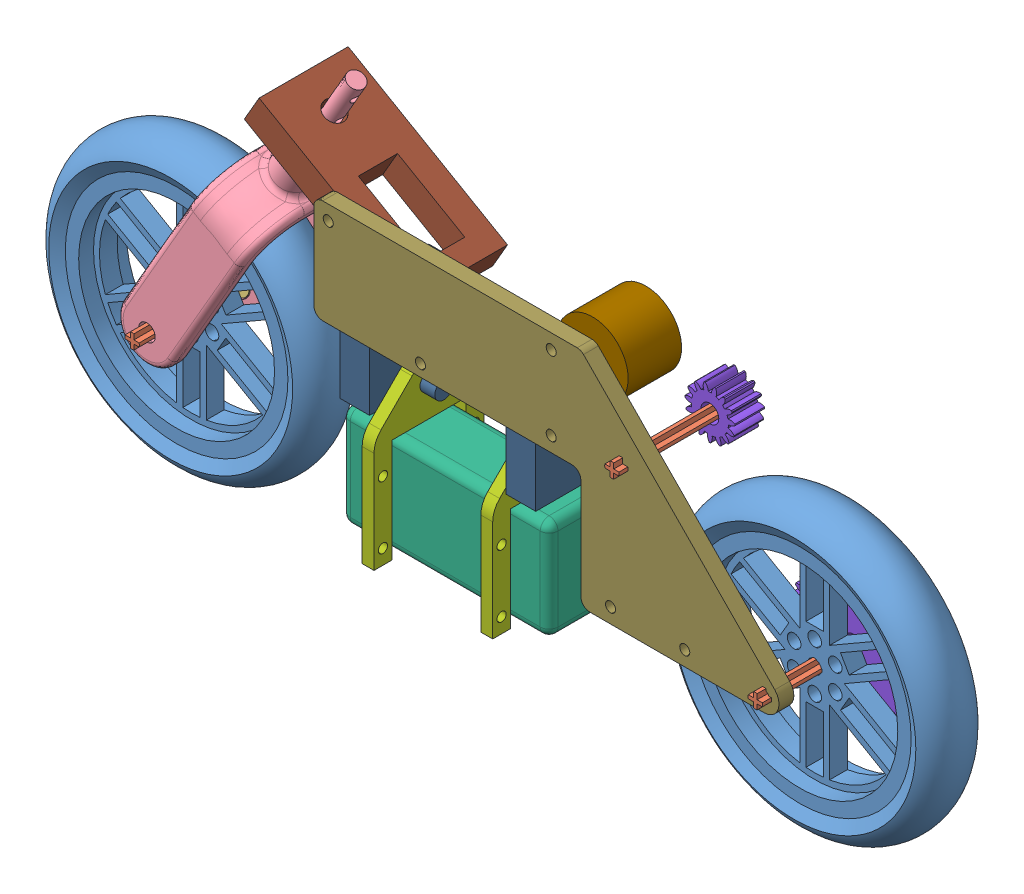
SolidWorks assembly assembly_v3.1, configuration 默认. Lengths in mm.
Overall size (305 143.43 89.5).
19 component instances, 12 part files, 41 mates.
Components (placement in the parent):
- tire_v2.0-1: tire_v2.0 [默认] at (-32.3319 -6.7834 95) size (95 95 20)
- axle_v1.0-1: axle_v1.0 [默认] at (-32.3319 -6.7834 95) x (0 0 -1) z (1 0 0) size (46 4.9 4.9)
- bearing_MR95ZZ-1: bearing_MR95ZZ [默认] at (-32.3319 -6.7834 110) x (0 0 -1) z (1 0 0) size (3 9 9)
- bearing_MR95ZZ-2: bearing_MR95ZZ [默认] at (-32.3319 -6.7834 83) x (0 0 -1) z (1 0 0) size (3 9 9)
- front_fork_v2.2-1: front_fork_v2.2 [默认] at (-2.3319 45.1782 95) x (0 0 -1) z (0.866025 -0.5 0) size (36 115 20)
- bearing_686ZZ-1: bearing_686ZZ [默认] at (7.8681 62.8451 95) x (0.5 0.866025 0) z (0 0 1) size (5 13 13)
- battery_v2.0-1: battery_v2.0 [默认] at (60.682 -20 95) x (-1 0 0) z (0 0 1) size (70 34 21)
- tire_v2.0-2: tire_v2.0 [默认] at (177.6681 -6.7834 95) size (95 95 20)
- battery_holder-1: battery_holder [默认] at (40.682 -37.5 95) x (0 0 -1) z (1 0 0) size (37 52.69 4)
- battery_holder-2: battery_holder [默认] at (80.682 -37.5 95) x (0 0 -1) z (1 0 0) size (37 52.69 4)
- spur gear_gb-2: spur gear_gb [GB - Spur gear 1M 40T 20PA 10FW ---S40A75H50L6.0N] at (177.6681 -6.7834 85) x (0 0 -1) z (1 0 0) size (10 41.91 41.91)
- spur gear_gb-4: spur gear_gb [GB - Spur gear 1M 15T 20PA 10FW ---S15A75H50L6.0N] at (129.3618 36.3945 85) x (0 0 -1) z (1 0 0) size (10 16.86 16.95)
- axle_v1.0-2: axle_v1.0 [默认] at (177.6681 -6.7834 95) x (0 0 -1) z (1 0 0) size (46 4.9 4.9)
- axle_v1.0-3: axle_v1.0 [默认] at (129.3618 36.3945 95) x (0 0 -1) z (1 0 0) size (46 4.9 4.9)
- motor_v1.0-1: motor_v1.0 [默认] at (107.8169 50.8219 85) x (0 0 1) z (-1 0 0) size (26 24 24)
- battery_frame_v1.0-1: battery_frame_v1.0 [默认] at (34.682 18.5 80) x (0 0 1) z (-1 0 0) size (30 30 20)
- battery_frame_v1.0-2: battery_frame_v1.0 [默认] at (90.682 18.5 110) x (0 0 -1) z (1 0 0) size (30 30 20)
- fork_frame_v1.0-1: fork_frame_v1.0 [默认] at (10.3681 67.1752 95) x (0 0 1) z (-0.866025 0.5 0) size (30 10 62)
- side_plate_v1.0-1: side_plate_v1.0 [默认] at (115.8979 -11.7834 110) x (0 0 1) z (-1 0 0) size (86.5 90.86 175.34)
Mates (geometry in assembly coordinates):
- 重合1: coincident anti-aligned: plane of tire_v2.0-1 through (-32.3319 -6.7834 95) normal (0 0 1); plane of axle_v1.0-1 through (-32.3319 -6.7834 95) normal (0 0 -1)
- 同心1: concentric anti-aligned: circle of tire_v2.0-1; circle of axle_v1.0-1
- 同心2: concentric anti-aligned: circle of bearing_MR95ZZ-1; circle of tire_v2.0-1
- 同心3: concentric anti-aligned: circle of bearing_MR95ZZ-2; circle of tire_v2.0-1
- 同心4: concentric aligned: circle of axle_v1.0-1; circle of ?
- 重合4: coincident anti-aligned: plane of tire_v2.0-1 through (-32.3319 -6.7834 95) normal (0 0 1); plane of ? through (3.6681 55.5705 95) normal (0 0 -1)
- 角度1: planar angle = 0.523599 rad aligned: plane of ? through (3.6681 55.5705 95) normal (0.866025 -0.5 0); plane of assembly through (0 0 0) normal (1 0 0)
- 距离1: distance = 9 mm anti-aligned: plane of tire_v2.0-1 through (-32.3319 -6.7834 98) normal (0 0 1); plane of bearing_MR95ZZ-1 through (-32.3319 -6.7834 107) normal (0 0 -1)
- 重合7: coincident anti-aligned: plane of tire_v2.0-1 through (-32.3319 -6.7834 95) normal (0 0 1); plane of front_fork_v2.2-1 through (-2.3319 45.1782 95) normal (0 0 -1)
- 同心5: concentric anti-aligned: circle of front_fork_v2.2-1; circle of tire_v2.0-1
- 角度2: planar angle = 2.094395 rad aligned: plane of front_fork_v2.2-1 through (-2.3319 45.1782 95) normal (0.866025 -0.5 0); plane of assembly through (0 0 0) normal (0 1 0)
- 距离2: distance = 9 mm anti-aligned: plane of tire_v2.0-1 through (-32.3319 -6.7834 92) normal (0 0 -1); plane of bearing_MR95ZZ-2 through (-32.3319 -6.7834 83) normal (0 0 1)
- 距离3: distance = 0.4 mm anti-aligned: plane of front_fork_v2.2-1 through (7.6681 62.4987 95) normal (0.5 0.866025 0); plane of bearing_686ZZ-1 through (7.8681 62.8451 95) normal (-0.5 -0.866025 0)
- 同心6: concentric aligned: circle of front_fork_v2.2-1; circle of bearing_686ZZ-1
- 重合11: coincident aligned: plane of tire_v2.0-1 through (-32.3319 -6.7834 95) normal (0 0 1); plane of battery_v2.0-1 through (60.682 -20 95) normal (0 0 1)
- 重合12: coincident aligned: plane of tire_v2.0-1 through (-32.3319 -6.7834 95) normal (0 0 1); plane of tire_v2.0-2 through (177.6681 -6.7834 95) normal (0 0 1)
- 距离4: distance = 210 mm aligned: plane of tire_v2.0-1 through (-32.3319 -6.7834 95) normal (1 0 0); plane of tire_v2.0-2 through (177.6681 -6.7834 95) normal (1 0 0)
- 重合14: coincident aligned: plane of tire_v2.0-1 through (-32.3319 -6.7834 95) normal (0 1 0); plane of tire_v2.0-2 through (177.6681 -6.7834 95) normal (0 1 0)
- 重合15: coincident aligned: plane of front_fork_v2.2-1 through (20.1681 84.1493 95) normal (0.5 0.866025 0); plane of ? through (20.1649 84.1512 95.0037) normal (0.5 0.866025 0)
- 距离6: distance = 20 mm anti-aligned: plane of battery_v2.0-1 through (60.682 -20 95) normal (-1 0 0); plane of battery_holder-1 through (40.682 -37.5 95) normal (1 0 0)
- 重合19: coincident anti-aligned: plane of battery_v2.0-1 through (60.682 -20 95) normal (0 0 1); plane of battery_holder-1 through (40.682 -37.5 95) normal (0 0 -1)
- 距离5: distance = 0.5 mm anti-aligned: plane of battery_v2.0-1 through (60.682 -3 95) normal (0 1 0); plane of battery_holder-1 through (44.682 -2.5 107.5) normal (0 -1 0)
- 重合21: coincident anti-aligned: plane of battery_v2.0-1 through (60.682 -20 95) normal (0 0 1); plane of battery_holder-2 through (80.682 -37.5 95) normal (0 0 -1)
- 距离7: distance = 20 mm anti-aligned: plane of battery_v2.0-1 through (60.682 -20 95) normal (-1 0 0); plane of battery_holder-2 through (80.682 -37.5 95) normal (1 0 0)
- 距离8: distance = 0.5 mm anti-aligned: plane of battery_v2.0-1 through (60.682 -3 95) normal (0 1 0); plane of battery_holder-2 through (84.682 -2.5 107.5) normal (0 -1 0)
- 重合24: coincident anti-aligned: plane of tire_v2.0-2 through (177.6681 -6.7834 95) normal (0 0 1); plane of axle_v1.0-2 through (177.6681 -6.7834 95) normal (0 0 -1)
- 同心7: concentric anti-aligned: circle of tire_v2.0-2; circle of axle_v1.0-2
- 同心8: concentric anti-aligned: circle of tire_v2.0-2; circle of spur gear_gb-2
- 距离9: distance = 10 mm anti-aligned: plane of spur gear_gb-2 through (177.6681 -6.7834 85) normal (0 0 -1); plane of tire_v2.0-2 through (177.6681 -6.7834 95) normal (0 0 1)
- 距离10: distance = 10 mm anti-aligned: plane of tire_v2.0-2 through (177.6681 -6.7834 95) normal (0 0 1); plane of spur gear_gb-4 through (129.3618 36.3945 85) normal (0 0 -1)
- 重合28: coincident anti-aligned: plane of tire_v2.0-1 through (-32.3319 -6.7834 95) normal (0 0 1); plane of axle_v1.0-3 through (129.3618 36.3945 95) normal (0 0 -1)
- 同心9: concentric anti-aligned: circle of spur gear_gb-4; circle of axle_v1.0-3
- 距离11: distance = 10 mm aligned: plane of motor_v1.0-1 through (107.8169 50.8219 85) normal (0 0 1); plane of tire_v2.0-1 through (-32.3319 -6.7834 95) normal (0 0 1)
- 同心10: concentric aligned: circle of battery_holder-1; circle of battery_frame_v1.0-1
- 距离12: distance = 1 mm anti-aligned: plane of battery_frame_v1.0-1 through (39.682 33.5 110) normal (1 0 0); plane of battery_holder-1 through (40.682 -37.5 95) normal (-1 0 0)
- 距离13: distance = 20 mm anti-aligned: plane of battery_v2.0-1 through (60.682 -20 95) normal (0 -1 0); plane of assembly through (0 0 0) normal (0 1 0)
- 同心11: concentric anti-aligned: circle of battery_holder-2; circle of battery_frame_v1.0-2
- 距离14: distance = 1 mm anti-aligned: plane of battery_frame_v1.0-2 through (85.682 33.5 80) normal (-1 0 0); plane of battery_holder-2 through (84.682 -37.5 95) normal (1 0 0)
- 重合35: coincident aligned: circle of bearing_686ZZ-1; circle of fork_frame_v1.0-1
- 同心12: concentric aligned: circle of tire_v2.0-2; circle of side_plate_v1.0-1
- 重合36: coincident anti-aligned: plane of fork_frame_v1.0-1 through (10.3681 67.1752 110) normal (0 0 1); plane of side_plate_v1.0-1 through (177.6681 -6.7834 110) normal (0 0 -1)
